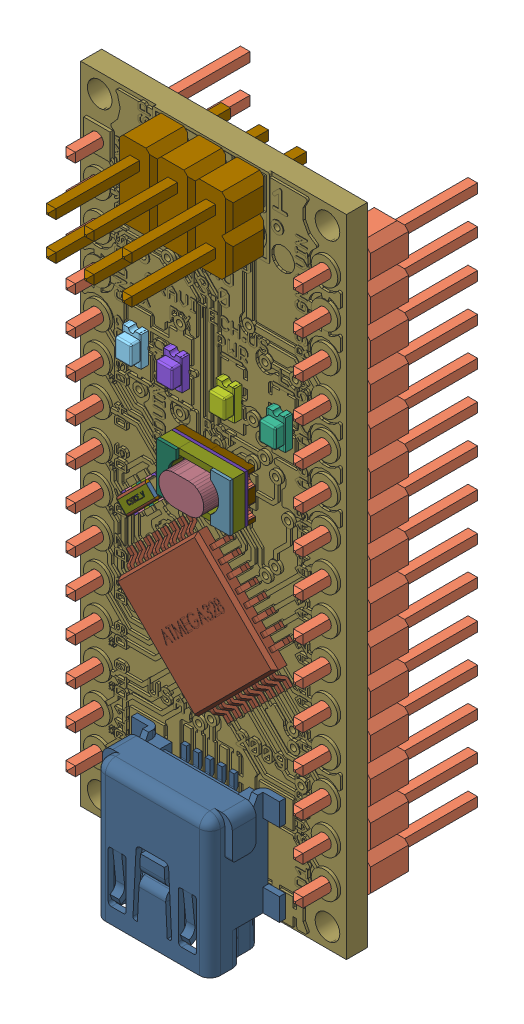
SolidWorks assembly User Library-Nano-1, configuration Default. Lengths in mm.
Overall size (17.79 44.92 18.56).
51 component instances, 39 part files, 0 mates.
Components (placement in the parent):
- User Library-Nano-1_Nano-Part-1-1: User Library-Nano-1_Nano-Part-1 [Default] at (-1.09 23.7 -1.55) x (1 0 0) z (0 1 0) size (3.2 0.65 1.6)
- User Library-Nano-1_User Library-Arduino Nano 3.0_HDR1x15-1: User Library-Nano-1_User Library-Arduino Nano 3.0_HDR1x15 [Default] at (-6.22 39.37 -1.6) x (0 -1 0) z (1 0 0) size (38.1 12.19 2.54)
- User Library-Nano-1_User Library-Arduino Nano 3.0_HDR1x15-2: User Library-Nano-1_User Library-Arduino Nano 3.0_HDR1x15 [Default] at (9.01 39.37 -1.6) x (0 -1 0) z (1 0 0) size (38.1 12.19 2.54)
- User Library-Nano-1_User Library-Arduino Nano 3.0_SOT-223-1: User Library-Nano-1_User Library-Arduino Nano 3.0_SOT-223 [Default] at (3.942 33.312 -2.33) x (1 0 0) z (0 1 0) size (6.5 1.68 6.96)
- User Library-Nano-1_User Library-Arduino Nano 3.0_User Library-SSOP-28-FT232RL_-1: User Library-Nano-1_User Library-Arduino Nano 3.0_User Library-SSOP-28-FT232RL_ [Default] at (1.38 10.3694 -1.55) x (-1 0 0) z (0 -1 0) size (7.76 2.15 10.33)
- User Library-Nano-1_Nano-Part-2-1: User Library-Nano-1_Nano-Part-2 [Default] at (-3.445 28.99 0.15) x (0 -1 0) z (0 0 1) size (2.02 1.25 1.1)
- User Library-Nano-1_Nano-Part-3-1: User Library-Nano-1_Nano-Part-3 [Default] at (-3.445 28.99 0.15) x (0 -1 0) z (0 0 1) size (2.02 1.25 1.1)
- User Library-Nano-1_Nano-Part-4-1: User Library-Nano-1_Nano-Part-4 [Default] at (-3.445 28.99 0.15) x (0 -1 0) z (0 0 1) size (2.02 1.25 1.1)
- User Library-Nano-1_Nano-Part-5-1: User Library-Nano-1_Nano-Part-5 [Default] at (-3.445 28.99 0.15) x (0 -1 0) z (0 0 1) size (2.02 1.25 1.1)
- User Library-Nano-1_User Library-Arduino Nano 3.0_HDR2x3-1: User Library-Nano-1_User Library-Arduino Nano 3.0_HDR2x3 [Default] at (-1.17 39.255 0.2) x (1 0 0) z (0 -1 0) size (7.62 12.19 5.08)
- User Library-Nano-1_NONE-1: User Library-Nano-1_NONE [Default] at (1.381 -1.74 2.15) x (1 0 0) z (0 -1 0) size (9.9 5.09 9.21)
- User Library-Nano-1_User Library-Arduino Nano 3.0_User Library-SW3dPS-atmega8 (tqfp32)_V2008_-1: User Library-Nano-1_User Library-Arduino Nano 3.0_User Library-SW3dPS-atmega8 (tqfp32)_V2008_ [Default] at (-0.3365 15.5219 0.76) x (0.707107 0.707107 0) z (0.707107 -0.707107 0) size (9.6 1.11 9.6)
- User Library-Nano-1_Nano-Part-6-1: User Library-Nano-1_Nano-Part-6 [Default] at (-7.51 0 0) size (17.78 43.18 1.97)
- User Library-Nano-1_User Library-CSTCE_V-1_Board1-1: User Library-Nano-1_User Library-CSTCE_V-1_Board1 [Default] at (-3.3345 20.135 0.0435) x (0.707107 0.707107 0) z (0 0 1) size (0.01 0.01 0.11)
- User Library-Nano-1_User Library-LS8_Board_1-1: User Library-Nano-1_User Library-LS8_Board_1 [Default] at (0 23.2 0.0435) size (0.01 0.01 0.11)
- User Library-Nano-1_User Library-CSTCE_V-1_Extruded20-1: User Library-Nano-1_User Library-CSTCE_V-1_Extruded20 [Default] at (-2.1996 21.3053 1.15) x (0.707107 0.707107 0) z (0 0 1) size (0.24 0.29 0.01)
- User Library-Nano-1_User Library-CSTCE_V-1_Extruded15-1: User Library-Nano-1_User Library-CSTCE_V-1_Extruded15 [Default] at (-2.6628 20.8068 1) x (0.707107 0.707107 0) z (0 0 1) size (2.7 0.8 0.15)
- User Library-Nano-1_User Library-CSTCE_V-1_Extruded14-1: User Library-Nano-1_User Library-CSTCE_V-1_Extruded14 [Default] at (-3.1471 20.3578 1.15) x (0.707107 0.707107 0) z (0 0 1) size (0.22 0.29 0.01)
- User Library-Nano-1_User Library-CSTCE_V-1_Extruded14-2: User Library-Nano-1_User Library-CSTCE_V-1_Extruded14 [Default] at (-2.6734 20.8315 1.15) x (0.707107 0.707107 0) z (0 0 1) size (0.22 0.29 0.01)
- User Library-Nano-1_User Library-CSTCE_V-1_Extruded17-1: User Library-Nano-1_User Library-CSTCE_V-1_Extruded17 [Default] at (-2.235 21.0861 1.15) x (0.707107 0.707107 0) z (0 0 1) size (0.22 0.03 0.01)
- User Library-Nano-1_User Library-CSTCE_V-1_Extruded21-1: User Library-Nano-1_User Library-CSTCE_V-1_Extruded21 [Default] at (-2.5072 20.9977 1.15) x (0.707107 0.707107 0) z (0 0 1) size (0.19 0.29 0.01)
- User Library-Nano-1_User Library-CSTCE_V-1_Extruded25-1: User Library-Nano-1_User Library-CSTCE_V-1_Extruded25 [Default] at (-2.8183 20.6866 1.15) x (0.707107 0.707107 0) z (0 0 1) size (0.19 0.29 0.01)
- User Library-Nano-1_User Library-CSTCE_V-1_Extruded23-1: User Library-Nano-1_User Library-CSTCE_V-1_Extruded23 [Default] at (-2.9739 20.531 1.15) x (0.707107 0.707107 0) z (0 0 1) size (0.21 0.29 0.01)
- User Library-Nano-1_User Library-CSTCE_V-1_Extruded18-1: User Library-Nano-1_User Library-CSTCE_V-1_Extruded18 [Default] at (-3.3345 20.135 0.15) x (0.707107 0.707107 0) z (0 0 1) size (0.6 1.3 0.4)
- User Library-Nano-1_User Library-CSTCE_V-1_Extruded18-2: User Library-Nano-1_User Library-CSTCE_V-1_Extruded18 [Default] at (-1.991 21.4785 0.15) x (0.707107 0.707107 0) z (0 0 1) size (0.6 1.3 0.4)
- User Library-Nano-1_User Library-CSTCE_V-1_Extruded16-1: User Library-Nano-1_User Library-CSTCE_V-1_Extruded16 [Default] at (-2.6628 20.8068 0.15) x (0.707107 0.707107 0) z (0 0 1) size (0.4 1.3 0.3)
- User Library-Nano-1_User Library-CSTCE_V-1_Extruded13-1: User Library-Nano-1_User Library-CSTCE_V-1_Extruded13 [Default] at (-2.6628 20.8068 0.45) x (0.707107 0.707107 0) z (0 0 1) size (0.4 1.3 0.1)
- User Library-Nano-1_User Library-CSTCE_V-1_Extruded24-1: User Library-Nano-1_User Library-CSTCE_V-1_Extruded24 [Default] at (-2.9633 20.5063 0.15) x (0.707107 0.707107 0) z (0 0 1) size (0.45 1.3 0.4)
- User Library-Nano-1_User Library-CSTCE_V-1_Extruded24-2: User Library-Nano-1_User Library-CSTCE_V-1_Extruded24 [Default] at (-2.3623 21.1073 0.15) x (0.707107 0.707107 0) z (0 0 1) size (0.45 1.3 0.4)
- User Library-Nano-1_User Library-CSTCE_V-1_Extruded22-1: User Library-Nano-1_User Library-CSTCE_V-1_Extruded22 [Default] at (-3.6704 19.7992 0.15) x (0.707107 0.707107 0) z (0 0 1) size (0.35 1.3 0.4)
- User Library-Nano-1_User Library-CSTCE_V-1_Extruded22-2: User Library-Nano-1_User Library-CSTCE_V-1_Extruded22 [Default] at (-1.6552 21.8144 0.15) x (0.707107 0.707107 0) z (0 0 1) size (0.35 1.3 0.4)
- User Library-Nano-1_User Library-CSTCE_V-1_Sphere1-1: User Library-Nano-1_User Library-CSTCE_V-1_Sphere1 [Default] at (-3.3352 19.5678 1) x (0.707107 0.707107 0) z (0 0 1) size (0.3 0.3 0.3)
- User Library-Nano-1_User Library-CSTCE_V-1_Sphere1-2: User Library-Nano-1_User Library-CSTCE_V-1_Sphere1 [Default] at (-1.9915 22.0447 1) x (0.707107 0.707107 0) z (0 0 1) size (0.3 0.3 0.3)
- User Library-Nano-1_User Library-CSTCE_V-1_Sphere1-3: User Library-Nano-1_User Library-CSTCE_V-1_Sphere1 [Default] at (-1.4249 21.4781 1) x (0.707107 0.707107 0) z (0 0 1) size (0.3 0.3 0.3)
- User Library-Nano-1_User Library-CSTCE_V-1_Sphere1-4: User Library-Nano-1_User Library-CSTCE_V-1_Sphere1 [Default] at (-3.9018 20.1344 1) x (0.707107 0.707107 0) z (0 0 1) size (0.3 0.3 0.3)
- User Library-Nano-1_User Library-CSTCE_V-1_Cylinder3-1: User Library-Nano-1_User Library-CSTCE_V-1_Cylinder3 [Default] at (-1.9832 22.037 1) x (0.707107 0.707107 0) z (0.707107 -0.707107 0) size (0.3 0.3 0.78)
- User Library-Nano-1_User Library-CSTCE_V-1_Cylinder3-2: User Library-Nano-1_User Library-CSTCE_V-1_Cylinder3 [Default] at (-3.8938 20.1264 1) x (0.707107 0.707107 0) z (0.707107 -0.707107 0) size (0.3 0.3 0.78)
- User Library-Nano-1_User Library-CSTCE_V-1_Cylinder2-1: User Library-Nano-1_User Library-CSTCE_V-1_Cylinder2 [Default] at (-3.3271 19.575 1) x (-0.707107 0.707107 0) z (0.707107 0.707107 0) size (0.3 0.3 2.68)
- User Library-Nano-1_User Library-CSTCE_V-1_Cylinder2-2: User Library-Nano-1_User Library-CSTCE_V-1_Cylinder2 [Default] at (-3.8927 20.1427 1) x (-0.707107 0.707107 0) z (0.707107 0.707107 0) size (0.3 0.3 2.68)
- User Library-Nano-1_User Library-CSTCE_V-1_Extruded19-1: User Library-Nano-1_User Library-CSTCE_V-1_Extruded19 [Default] at (-2.6628 20.8068 0.55) x (0.707107 0.707107 0) z (0 0 1) size (3 1.1 0.45)
- User Library-Nano-1_User Library-LS8_Extruded_9-1: User Library-Nano-1_User Library-LS8_Extruded_9 [Default] at (1.87 24.1 0.85) size (3 2 1.8)
- User Library-Nano-1_User Library-LS8_Extruded_10-1: User Library-Nano-1_User Library-LS8_Extruded_10 [Default] at (3.672 24.1 1.65) size (1.3 3.2 0.2)
- User Library-Nano-1_User Library-LS8_Extruded_11-1: User Library-Nano-1_User Library-LS8_Extruded_11 [Default] at (0.068 24.1 1.65) size (1.3 3.2 0.2)
- User Library-Nano-1_User Library-LS8_Extruded_12-1: User Library-Nano-1_User Library-LS8_Extruded_12 [Default] at (1.87 24.1 0.85) size (4.9 3.2 0.8)
- User Library-Nano-1_User Library-LS8_Extruded_13-1: User Library-Nano-1_User Library-LS8_Extruded_13 [Default] at (1.87 24.1 0.65) size (4.9 3.2 0.2)
- User Library-Nano-1_User Library-LS8_Extruded_14-1: User Library-Nano-1_User Library-LS8_Extruded_14 [Default] at (1.87 24.1 0.15) size (4.9 3.2 0.5)
- User Library-Nano-1_User Library-LS8_Extruded_15-1: User Library-Nano-1_User Library-LS8_Extruded_15 [Default] at (1.87 24.1 0.15) size (2.8 2.9 0.5)
- User Library-Nano-1_User Library-LS8_Extruded_16-1: User Library-Nano-1_User Library-LS8_Extruded_16 [Default] at (3.945 23.2 0.15) size (0.75 1.1 0.5)
- User Library-Nano-1_User Library-LS8_Extruded_16-2: User Library-Nano-1_User Library-LS8_Extruded_16 [Default] at (3.945 25 0.15) size (0.75 1.1 0.5)
- User Library-Nano-1_User Library-LS8_Extruded_17-1: User Library-Nano-1_User Library-LS8_Extruded_17 [Default] at (-0.205 23.2 0.15) size (0.75 1.1 0.5)
- User Library-Nano-1_User Library-LS8_Extruded_17-2: User Library-Nano-1_User Library-LS8_Extruded_17 [Default] at (-0.205 25 0.15) size (0.75 1.1 0.5)
